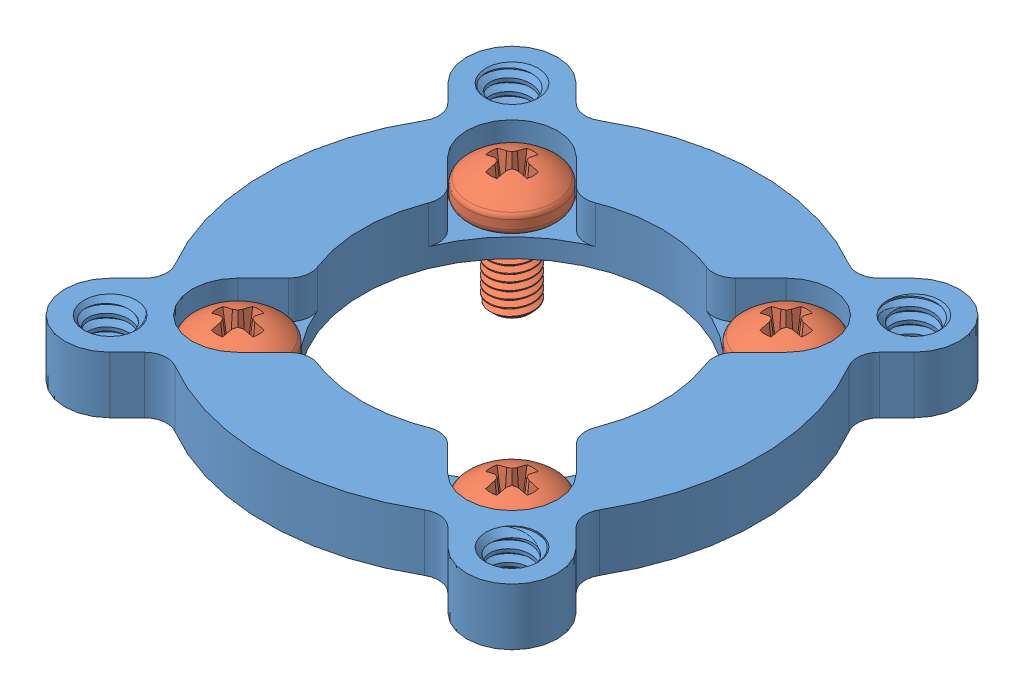
SolidWorks assembly Motor_mount, configuration Default. Lengths in mm.
Overall size (33.02 8.74 33.02).
5 component instances, 2 part files, 0 mates.
Components (placement in the parent):
- 555174-1: 555174 [Default] at (-58.8675 33.2863 7.1552) size (33.02 4.05 33.02)
- 555174 screw_92005A116-1: 555174 screw_92005A116 [Default] at (-68.0596 28.5563 -2.0369) x (1 0 0) z (0 1 0) size (6 6 8.48)
- 555174 screw_92005A116-2: 555174 screw_92005A116 [Default] at (-68.0596 28.5563 16.3474) x (0 0 -1) z (0 1 0) size (6 6 8.48)
- 555174 screw_92005A116-3: 555174 screw_92005A116 [Default] at (-49.6753 28.5563 16.3474) x (-1 0 0) z (0 1 0) size (6 6 8.48)
- 555174 screw_92005A116-4: 555174 screw_92005A116 [Default] at (-49.6753 28.5563 -2.0369) x (0 0 1) z (0 1 0) size (6 6 8.48)
